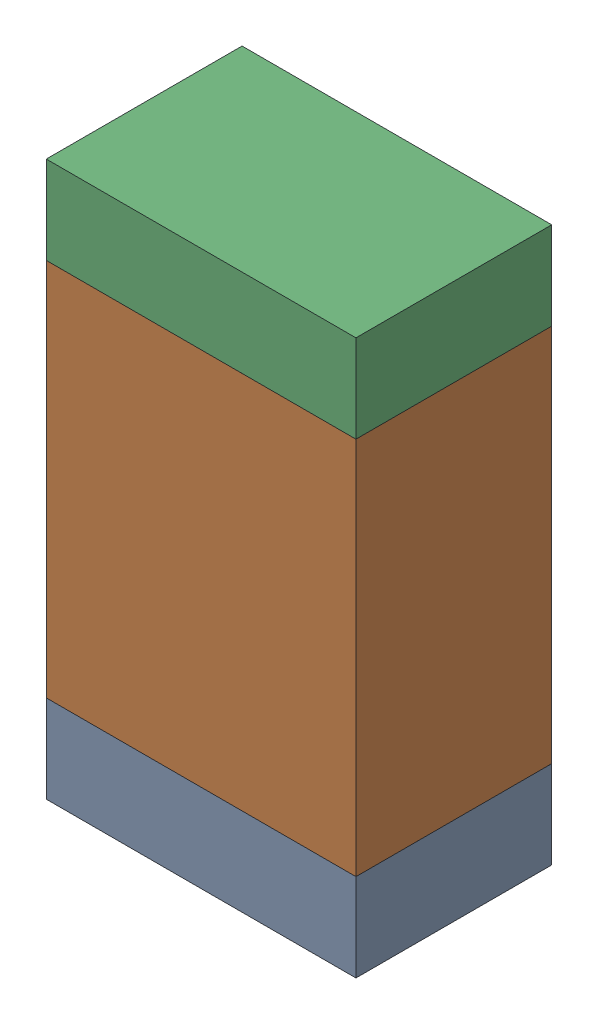
SolidWorks assembly R5, configuration Default. Lengths in mm.
Overall size (0.95 1.7 0.6).
6 component instances, 2 part files, 0 mates.
Components (placement in the parent):
- 959206216-1: 959206216 [Default] at (120.9041 81.6699 0) size (0.95 0.27 0.6)
  - Extruded-1: Extruded [Default] at origin size (0.95 0.27 0.6)
- 959206352-1: 959206352 [Default] at (120.9041 82.3849 0) size (0.95 1.16 0.6)
  - Extruded-1-1: Extruded-1 [Default] at origin size (0.95 1.16 0.6)
- 959206216-2: 959206216 [Default] at (120.9041 83.0999 0) size (0.95 0.27 0.6)
  - Extruded-1: Extruded [Default] at origin size (0.95 0.27 0.6)
